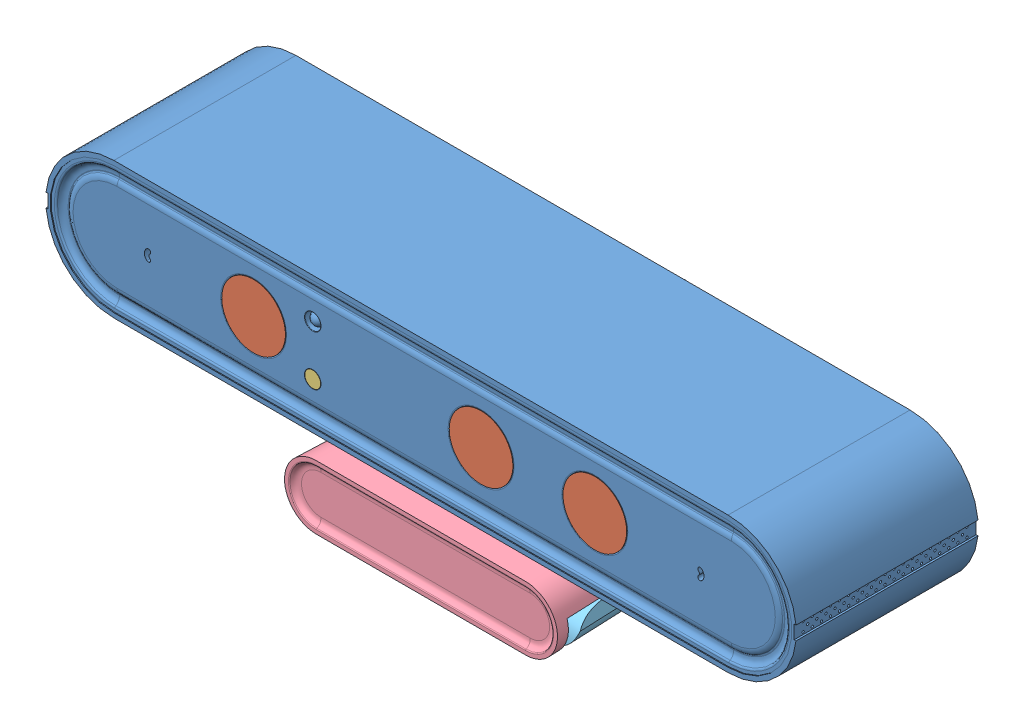
SolidWorks assembly Orbbec Astra Camera, configuration Default. Lengths in mm.
Overall size (164.85 49 60.06).
8 component instances, 5 part files, 6 mates.
Components (placement in the parent):
- Main_Body-1: Main_Body [Default] at origin size (164.85 35.05 58.1)
  - MainBody-1: MainBody [Default] at origin size (164.85 35.05 58.1)
  - Glass1-1: Glass1 [Default] at (72.1398 14.3643 -2.4) x (-0.923728 -0.383049 0) z (0 0 -1) size (14 14 1)
  - Glass1-2: Glass1 [Default] at (47.1398 14.3643 -2.4) x (-0.923728 -0.383049 0) z (0 0 -1) size (14 14 1)
  - Glass1-3: Glass1 [Default] at (-75 0 0) size (14 14 1)
  - SGlass1-1: SGlass1 [Default] at (-49.2381 -9.8042 -2.4) x (-0.923728 -0.383049 0) z (0 0 -1) size (3.5 3.5 1)
- Mount_Part1-1: Mount_Part1 [Default] at origin size (60.35 17.75 60.06)
- Mount_Part2-1: Mount_Part2 [Default] at origin size (59.01 8.61 55.01)
Mates (geometry in assembly coordinates):
- Width2: width anti-aligned: plane of Mount_Part1-1 through (12.6 0 0) normal (-1 0 0); plane of Mount_Part1-1 through (-12.6 0 0) normal (1 0 0); plane of Main_Body-1/MainBody-1 through (12.5 -20 -7.5) normal (1 0 0); plane of Main_Body-1/MainBody-1 through (-12.5 -20 -7.5) normal (-1 0 0)
- Concentric5: concentric aligned: cylinder of Mount_Part1-1 through (-500000 -18.4 -11.25) axis (1 0 0) radius 0.75; cylinder of Main_Body-1/MainBody-1 through (-82.501 -18.4 -11.25) axis (1 0 0) radius 0.75
- Width3: width anti-aligned: plane of Mount_Part1-1 through (-21 -24.9 0) normal (1 0 0); plane of Mount_Part1-1 through (21 -24.9 0) normal (-1 0 0); plane of Mount_Part2-1 through (20 55.7595 -60) normal (1 0 0); plane of Mount_Part2-1 through (-20 55.7595 -60) normal (-1 0 0)
- Concentric6: concentric anti-aligned: cylinder of Mount_Part2-1 through (22 -31.4 -56.25) axis (-1 0 0) radius 0.75; cylinder of Mount_Part1-1 through (-22.5 -31.4 -56.25) axis (1 0 0) radius 0.75
- LimitAngle1: limit planar angle = 0 rad aligned: plane of Main_Body-1/MainBody-1 through (0 0 0) normal (0 1 0); plane of Mount_Part1-1 through (0 0 0) normal (0 1 0)
- LimitAngle2: limit planar angle = 0 rad aligned: plane of Mount_Part2-1 through (0 0 0) normal (0 1 0); plane of Mount_Part1-1 through (0 0 0) normal (0 1 0)
